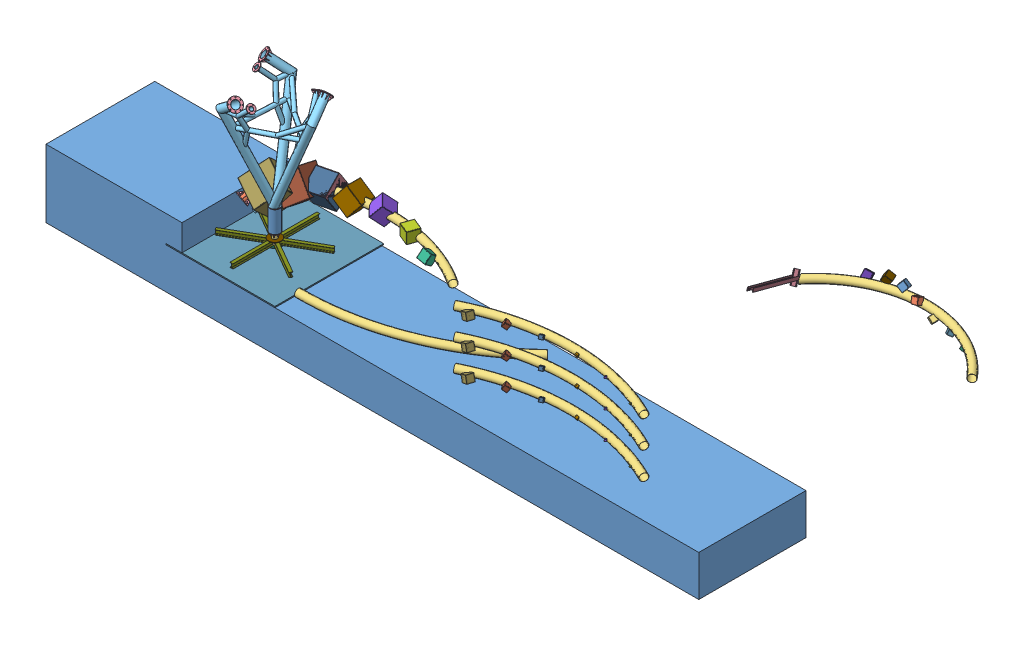
SolidWorks assembly loaded truck, configuration Default. Lengths in mm.
Overall size (16211.83 6656.86 12920.37).
99 component instances, 48 part files, 12 mates.
Components (placement in the parent):
- truck-1: truck [Default] at origin size (14630.4 1524 2438.4)
- tube1A-1: tube1A [Default] at (5444.0248 1828.8 -1151.975) size (10304.8 4797.57 11903.29)
  - tube1^tube1A-1: tube1^tube1A [A] at origin size (5509.57 567.54 3868.09) (virtual)
    - short-tube^tube1_tube1A-1: short-tube^tube1_tube1A [Default<As Machined>] at (-2066.9857 0 -335.3072) x (0.280011 0.524542 -0.804021) z (0.396988 0.699289 0.594471) size (592.32 168.28 168.28) (virtual)
    - tubes-1: tubes [tube1A] at origin size (5509.57 179.56 3868.09)
    - pipe_flange-1: pipe_flange [Default] at (-2222.5526 -291.4219 111.3861) x (0.228255 0.777129 0.58649) z (0.280011 0.524542 -0.804021) size (279.4 279.4 111.05)
  -  tube1-support-arm^tube1A-1:  tube1-support-arm^tube1A [Default] at (-1841.3383 3296.5765 733.9451) x (0.486192 -0.007064 0.873823) z (0.120148 -0.98993 -0.074853) size (412.01 1066.18 424.01) (virtual)
  - cube_positions-1: cube_positions [Default] at (-1823.1764 -3408.8204 760.8644) x (0.483946 0.016768 0.874937) z (-0.868168 0.134776 0.477619) size (10173.18 3894.08 5705.72) (hidden)
  - cube_21-2: cube_21 [Default] at (1288.2494 29.6746 -537.6975) x (0.984604 -0.16863 0.046022) z (-0.163622 -0.79651 0.582065) size (201.3 201.3 201.3)
  - cube_22-2: cube_22 [Default] at (645.1566 57.3606 -803.1505) x (0.933595 -0.053544 0.354308) z (-0.041789 -0.998295 -0.040754) size (257.18 257.18 257.18)
  - cube_23-2: cube_23 [Default] at (-109.9957 38.0914 -951.4494) x (0.687918 -0.154019 0.709258) z (-0.466636 0.654617 0.59475) size (324.08 323.21 324.08)
  - cube_24-2: cube_24 [Default] at (-714.1695 -0.9056 -890.2015) x (0.799244 -0.59975 -0.038856) z (0.182734 0.180907 0.966375) size (396.88 396.88 396.88)
  - cube_25-2: cube_25 [Default] at (-1245.7406 -40.6251 -805.9879) x (0.987297 0.085082 -0.134183) z (0.001435 0.839726 0.543009) size (473.08 473.08 473.08)
  - cube_26-2: cube_26 [Default] at (-1667.5795 -86.266 -627.0985) x (0.64678 -0.746775 0.15493) z (0.176738 0.344365 0.92205) size (549.27 549.27 549.27)
  - cube_27-2: cube_27 [Default] at (-1978.9147 -133.1093 -276.4109) x (0.852088 -0.443054 0.278657) z (0.115039 0.677912 0.726086) size (622.94 622.94 622.94)
  - boundry_cube-1: boundry_cube [cube25] at (-1244.4232 -38.3056 -806.6548) x (0.987297 0.085082 -0.134183) z (0.158877 -0.536304 0.828937) size (469.9 469.9 469.9)
  - boundry_cube-2: boundry_cube [cube26] at (-1667.1479 -83.6306 -626.4438) x (0.741916 0.568981 -0.354712) z (0.176738 0.344365 0.92205) size (546.1 546.1 546.1) (hidden)
  - boundry_cube-3: boundry_cube [cube27] at (-1979.2742 -130.3985 -276.6986) x (0.510601 0.586633 -0.628609) z (0.115039 0.677912 0.726086) size (619.76 619.76 619.76) (hidden)
- central_structure-1: central_structure [Default] at (3849.3756 1064.3199 -1156.3899) x (1 0 0) z (0 1 0) size (2438.4 2438.4 3268.86)
  - reference_cubes-1: reference_cubes [Default] at origin size (10937.47 5524.84 3894.08) (hidden)
  - scaffolding^central_structure-1: scaffolding^central_structure [Default] at (0 0 -124.5199) x (-1 0 0) z (0 1 0) size (2438.4 25.4 2438.4) (virtual)
    - reference_ground^scaffolding_central_structure-1: reference_ground^scaffolding_central_structure [Default] x (-1 0 0) z (0 1 0) size (2438.4 2438.4 25.4) (virtual)
  - ground_anchor-1: ground_anchor [Default] at (0 0 -124.5199) x (-1 0 0) z (0 1 0) size (1722.09 120.65 1949.45)
    - Copy of ground_anchor_ref^ground_anchor-1: Copy of ground_anchor_ref^ground_anchor [Default] at origin size (279.4 0 279.4) (virtual)
    - low_plate^ground_anchor-1: low_plate^ground_anchor [Default] at origin size (279.4 9.53 279.4) (virtual)
    - S Section_AI-1: S Section_AI [S4x7.7x36] at (-33.8201 9.525 -517.525) size (67.64 101.6 914.4)
    - S Section_AI-3: S Section_AI [S4x7.7x36] at (-465.0998 9.525 -229.4734) x (0.5 0 -0.866025) z (0.866025 0 0.5) size (67.64 101.6 914.4)
    - S Section_AI-4: S Section_AI [S4x7.7x36] at (-431.2797 9.525 288.0516) x (-0.5 0 -0.866025) z (0.866025 0 -0.5) size (67.64 101.6 914.4)
    - S Section_AI-5: S Section_AI [S4x7.7x36] at (33.8201 9.525 517.525) x (-1 0 0) z (0 0 -1) size (67.64 101.6 914.4)
    - S Section_AI-6: S Section_AI [S4x7.7x36] at (465.0998 9.525 229.4734) x (-0.5 0 0.866025) z (-0.866025 0 -0.5) size (67.64 101.6 914.4)
    - S Section_AI-7: S Section_AI [S4x7.7x36] at (431.2797 9.525 -288.0516) x (0.5 0 0.866025) z (-0.866025 0 0.5) size (67.64 101.6 914.4)
    - mid_plate^ground_anchor-2: mid_plate^ground_anchor [Default] at origin size (146.05 9.53 146.05) (virtual)
    - top_plate^ground_anchor-1: top_plate^ground_anchor [Default] at (0 111.125 0) x (-1 0 0) z (0 1 0) size (279.4 279.4 9.53) (virtual)
  - base_pin^central_structure-1: base_pin^central_structure [Default] at (0 0 367.6051) x (1 0 0) z (0 -1 0) size (219.07 736.6 219.07) (virtual)
    - tube^base_pin_central_structure-1: tube^base_pin_central_structure [Default] at origin size (219.07 482.6 219.07) (virtual)
    - plate^base_pin_central_structure-1: plate^base_pin_central_structure [Default] at (0 -254 0) size (219.07 12.7 219.07) (virtual)
    - plate^base_pin_central_structure-2: plate^base_pin_central_structure [Default] at (0 241.3 0) size (219.07 12.7 219.07) (virtual)
    - pin^base_pin_central_structure-1: pin^base_pin_central_structure [Default] at (0 -368.3 0) size (114.3 228.6 114.3) (virtual)
    - gusset^base_pin_central_structure-1: gusset^base_pin_central_structure [Default] at (0 -241.3 0) x (-1 0 0) z (0 0 -1) size (52.39 88.9 9.53) (virtual)
    - gusset^base_pin_central_structure-2: gusset^base_pin_central_structure [Default] at (0 -241.3 0) x (-0.5 0 -0.866025) z (0.866025 0 -0.5) size (52.39 88.9 9.53) (virtual)
    - gusset^base_pin_central_structure-3: gusset^base_pin_central_structure [Default] at (0 -241.3 0) x (0.5 0 -0.866025) z (0.866025 0 0.5) size (52.39 88.9 9.53) (virtual)
    - gusset^base_pin_central_structure-4: gusset^base_pin_central_structure [Default] at (0 -241.3 0) size (52.39 88.9 9.53) (virtual)
    - gusset^base_pin_central_structure-5: gusset^base_pin_central_structure [Default] at (0 -241.3 0) x (0.5 0 0.866025) z (-0.866025 0 0.5) size (52.39 88.9 9.53) (virtual)
    - gusset^base_pin_central_structure-6: gusset^base_pin_central_structure [Default] at (0 -241.3 0) x (-0.5 0 0.866025) z (-0.866025 0 -0.5) size (52.39 88.9 9.53) (virtual)
  - tubes^central_structure-1: tubes^central_structure [Default<As Machined>] at origin size (1730.45 1786.14 2430.89) (virtual)
  - pipe_flange-4: pipe_flange [Default] at (-40.8618 -842.5697 2971.914) x (-0.647876 -0.272848 0.711204) z (-0.761452 0.20604 -0.614604) size (279.4 279.4 111.05)
  - pipe_flange-5: pipe_flange [Default] at (-709.2559 456.6722 2971.914) x (0.087644 0.697501 0.711204) z (0.559162 0.556417 -0.614604) size (279.4 279.4 111.05)
  - pipe_flange-6: pipe_flange [Default] at (750.1177 385.8975 2971.914) x (0.560231 -0.424653 0.711204) z (0.20229 -0.762457 -0.614604) size (279.4 279.4 111.05)
  - pipe_flange-10: pipe_flange [Sch40_3_inch] at (125.9153 -655.6721 2881.7665) x (-0.595866 -0.523692 0.608844) z (-0.726669 0.028829 -0.686383) size (177.8 177.8 57.15)
  - pipe_flange-11: pipe_flange [Sch40_3_inch] at (-630.7864 218.7903 2881.7665) x (-0.155598 0.777881 0.608844) z (0.388301 0.614899 -0.686383) size (177.8 177.8 57.15)
  - pipe_flange-12: pipe_flange [Sch40_3_inch] at (504.8711 436.8819 2881.7665) x (0.751464 -0.254189 0.608844) z (0.338368 -0.643728 -0.686383) size (177.8 177.8 57.15)
  - positioning_ring^central_structure-1: positioning_ring^central_structure [Default] at (-467.1227 -648.6433 2658.0072) x (-0.32518 0.316298 -0.891186) z (0.945415 0.129823 -0.298891) size (41.91 20.96 5.08) (virtual)
  - positioning_ring^central_structure-2: positioning_ring^central_structure [Default] at (-328.1802 728.8618 2658.0072) x (0.436513 0.123465 -0.891186) z (-0.360278 -0.883665 -0.298891) size (41.91 20.96 5.08) (virtual)
  - positioning_ring^central_structure-3: positioning_ring^central_structure [Default] at (795.303 -80.2185 2658.0072) x (-0.111332 -0.439764 -0.891186) z (-0.585137 0.753842 -0.298891) size (41.91 20.96 5.08) (virtual)
- tube2A-1: tube2A [Default] at (10761.5629 1905 -128.1175) size (5548.73 212.13 5064.2)
  - tubes-1: tubes [tube2A] at origin size (5548.73 168.28 5064.2)
  - cube_15-2: cube_15 [Default] at (1757.1943 7.1888 -324.7748) x (0.466813 -0.378836 0.799105) z (-0.87943 -0.103618 0.464614) size (31.12 31.12 31.12)
  - cube_16-2: cube_16 [Default] at (968.8015 9.4519 -559.7177) x (0.806784 -0.069825 -0.586706) z (0.590423 0.132849 0.796085) size (41.27 41.27 42.23)
  - cube_17-2: cube_17 [Default] at (219.4124 11.792 -668.2944) x (0.954748 -0.289413 -0.068523) z (-0.098768 -0.525851 0.844823) size (59.24 59.06 59.06)
  - cube_18-2: cube_18 [Default] at (-522.2233 15.3473 -617.0525) x (0.916882 -0.004667 -0.399132) z (0.359767 0.442803 0.821276) size (81.92 81.92 84.87)
  - cube_19-2: cube_19 [Default] at (-1183.1884 -5.1426 -489.4193) x (0.660298 -0.557655 -0.503018) z (0.583277 -0.041114 0.811232) size (112.39 112.39 112.56)
  - cube_20-2: cube_20 [Default] at (-1812.0839 -23.6863 -257.1651) x (-0.350316 0.927365 -0.131426) z (-0.262185 0.037617 0.964284) size (157.73 157.73 159.27)
- tube2A-3: tube2A [Default] at (10761.5629 1295.4 -128.1175) size (5548.73 212.13 5064.2)
  - tubes-1: tubes [tube2A] at origin size (5548.73 168.28 5064.2)
  - cube_15-2: cube_15 [Default] at (1757.1943 7.1888 -324.7748) x (0.466813 -0.378836 0.799105) z (-0.87943 -0.103618 0.464614) size (31.12 31.12 31.12)
  - cube_16-2: cube_16 [Default] at (968.8015 9.4519 -559.7177) x (0.806784 -0.069825 -0.586706) z (0.590423 0.132849 0.796085) size (41.27 41.27 42.23)
  - cube_17-2: cube_17 [Default] at (219.4124 11.792 -668.2944) x (0.954748 -0.289413 -0.068523) z (-0.098768 -0.525851 0.844823) size (59.24 59.06 59.06)
  - cube_18-2: cube_18 [Default] at (-522.2233 15.3473 -617.0525) x (0.916882 -0.004667 -0.399132) z (0.359767 0.442803 0.821276) size (81.92 81.92 84.87)
  - cube_19-2: cube_19 [Default] at (-1183.1884 -5.1426 -489.4193) x (0.660298 -0.557655 -0.503018) z (0.583277 -0.041114 0.811232) size (112.39 112.39 112.56)
  - cube_20-2: cube_20 [Default] at (-1812.0839 -23.6863 -257.1651) x (-0.350316 0.927365 -0.131426) z (-0.262185 0.037617 0.964284) size (157.73 157.73 159.27)
- tube2A-4: tube2A [Default] at (10761.5629 2514.6 -128.1175) size (5548.73 212.13 5064.2)
  - tubes-1: tubes [tube2A] at origin size (5548.73 168.28 5064.2)
  - cube_15-2: cube_15 [Default] at (1757.1943 7.1888 -324.7748) x (0.466813 -0.378836 0.799105) z (-0.87943 -0.103618 0.464614) size (31.12 31.12 31.12)
  - cube_16-2: cube_16 [Default] at (968.8015 9.4519 -559.7177) x (0.806784 -0.069825 -0.586706) z (0.590423 0.132849 0.796085) size (41.27 41.27 42.23)
  - cube_17-2: cube_17 [Default] at (219.4124 11.792 -668.2944) x (0.954748 -0.289413 -0.068523) z (-0.098768 -0.525851 0.844823) size (59.24 59.06 59.06)
  - cube_18-2: cube_18 [Default] at (-522.2233 15.3473 -617.0525) x (0.916882 -0.004667 -0.399132) z (0.359767 0.442803 0.821276) size (81.92 81.92 84.87)
  - cube_19-2: cube_19 [Default] at (-1183.1884 -5.1426 -489.4193) x (0.660298 -0.557655 -0.503018) z (0.583277 -0.041114 0.811232) size (112.39 112.39 112.56)
  - cube_20-2: cube_20 [Default] at (-1812.0839 -23.6863 -257.1651) x (-0.350316 0.927365 -0.131426) z (-0.262185 0.037617 0.964284) size (157.73 157.73 159.27)
- tube4A-1: tube4A [Default] at (11562.999 2511.1486 -4732.0499) x (0.194163 -0.849473 0.490608) z (0.490608 0.517175 0.701309) size (11936.67 6342.03 7419.9)
  - cube_positions-1: cube_positions [Default] at (8904.7669 0 -1666.8962) x (-0.98414 0 0.177396) z (-0.177396 0 -0.98414) size (10173.18 3894.08 5705.72) (hidden)
  - ground_anchor^tube4A-1: ground_anchor^tube4A [Default] at (9566.8333 -60.325 -1104.0246) x (-0.999452 0 0.033088) z (0 -1 0) size (470.34 5095.97 101.6) (virtual)
  - tubes-1: tubes [tube4A] at (840.8937 1535.1212 -511.9514) x (0.194163 0.849473 0.490608) z (0.490608 -0.517175 0.701309) size (5156.33 178.46 3757.36)
  - cube_06-2: cube_06 [Default] at (471.5315 2748.7735 -1138.0748) x (0.201369 0.905147 -0.374379) z (0.964745 -0.249399 -0.084066) size (112.39 112.39 116.4)
  - cube_07-2: cube_07 [Default] at (645.566 3070.0096 -753.4371) x (0.234737 0.447214 -0.863075) z (0.927023 -0.370117 0.060349) size (97.16 97.16 101.09)
  - cube_08-2: cube_08 [Default] at (942.6163 3319.9065 -214.0269) x (-0.520827 0.525094 -0.673064) z (0.853659 0.322603 -0.408894) size (81.92 81.92 85.85)
  - cube_01-2: cube_01 [Default] at (-37.904 1151.3192 -1919.5434) x (-0.033713 0.00175 0.99943) z (-0.959686 0.279148 -0.032861) size (163.19 163.19 163.19)
  - cube_02-2: cube_02 [Default] at (-88.0911 1506.3364 -1758.7081) x (0.627621 -0.148413 0.764242) z (-0.63488 0.470576 0.612769) size (158.12 158.12 158.12)
  - cube_03-2: cube_03 [Default] at (-39.521 1804.2306 -1588.2847) x (0.643801 0.761931 -0.070581) z (-0.729232 0.638874 0.245073) size (150.61 150.49 150.49)
  - cube_04-2: cube_04 [Default] at (125.08 2085.0042 -1403.7965) x (0.992472 0.073499 -0.097969) z (-0.011929 0.85412 0.519939) size (140.33 142.17 140.33)
  - cube_05-2: cube_05 [Default] at (346.6784 2408.9309 -1315.8693) x (0.718959 0.693701 0.043313) z (-0.249968 0.199916 0.947391) size (127.64 128.2 127.64)
- tube3A-1: tube3A [Default] at (7335.3837 1295.4 -1113.8417) x (-0.929213 0 0.369544) z (-0.369544 0 -0.929213) size (5554.54 175.44 6144.47)
  - cube_positions-1: cube_positions [Default] at (-2670.6643 -3280.6684 6355.7547) x (0.67216 -0.00431 -0.740393) z (0.73275 0.147305 0.664364) size (10173.18 3894.08 5705.72) (suppressed, hidden)
  - tubes-1: tubes [tube3A] at origin size (5554.54 168.28 6144.47)
  - cube_09-2: cube_09 [Default] at (1891.328 -39.9576 -219.9855) x (0.558213 -0.291956 0.776634) z (-0.686222 0.363684 0.629947) size (66.67 66.67 66.67)
  - cube_10-2: cube_10 [Default] at (1228.5614 -17.4711 -418.2438) x (-0.71669 -0.609869 -0.338254) z (-0.59783 0.78702 -0.152311) size (53.98 55.56 54.09)
  - cube_11-2: cube_11 [Default] at (417.5304 -1.7159 -528.0192) x (0.316006 -0.604945 0.730877) z (0.798081 0.586057 0.140015) size (46.52 46.39 46.35)
  - cube_12-2: cube_12 [Default] at (-358.2393 3.7306 -535.1453) x (0.586492 0.345764 0.732445) z (-0.809811 0.233265 0.538324) size (33.65 33.65 33.65)
  - cube_13-2: cube_13 [Default] at (-1020.6914 4.0423 -454.5155) x (0.910611 -0.27141 0.311647) z (0.00891 0.76683 0.641789) size (28.57 28.57 28.57)
  - cube_14-2: cube_14 [Default] at (-1799.1926 16.7711 -254.42) x (0.802946 -0.45597 -0.383887) z (0.528044 0.2454 0.812987) size (20.96 20.96 20.96)
Mates (geometry in assembly coordinates):
- Coincident2: coincident anti-aligned: plane of truck-1 through (2985.7756 914.4 -2340.2818) normal (0 1 0); plane of central_structure-1/scaffolding^central_structure-1/reference_ground^scaffolding_central_structure-1 through (2630.1756 914.4 62.8101) normal (0 -1 0)
- Coincident3: coincident aligned: plane of truck-1 through (-62.2244 1524 62.8101) normal (0 0 1); plane of central_structure-1/scaffolding^central_structure-1/reference_ground^scaffolding_central_structure-1 through (5068.5756 914.4 62.8101) normal (0 0 1)
- Distance2: distance = 355.6 mm anti-aligned: plane of truck-1 through (2985.7756 1524 -2375.5899) normal (1 0 0); plane of central_structure-1/scaffolding^central_structure-1/reference_ground^scaffolding_central_structure-1 through (2630.1756 914.4 -2375.5899) normal (-1 0 0)
- Distance4: distance = 914.4 mm: point of tube1A-1/tube1^tube1A-1/tubes-1; plane of truck-1 through (2985.7756 914.4 -2340.2818) normal (0 1 0)
- Concentric2: concentric aligned: circle of tube2A-1/tubes-1; circle of tube2A-4/tubes-1
- Distance6: distance = 609.6 mm: point of tube2A-4/tubes-1; point of tube2A-1/tubes-1
- Concentric3: concentric aligned: circle of tube2A-3/tubes-1; circle of tube2A-4/tubes-1
- Distance8: distance = 1219.2 mm: point of tube2A-3/tubes-1; point of tube2A-4/tubes-1
- Distance9: distance = 381 mm: point of tube2A-3/tubes-1; plane of truck-1 through (2985.7756 914.4 -2340.2818) normal (0 1 0)
- Parallel5: parallel aligned: plane of truck-1 through (2985.7756 914.4 -2340.2818) normal (0 1 0); plane of tube4A-1
- Distance12: distance = 457.2 mm aligned: plane of tube4A-1; plane of truck-1 through (2985.7756 914.4 -2340.2818) normal (0 1 0)
- Distance13: distance = 381 mm: point of tube3A-1/tubes-1; plane of truck-1 through (2985.7756 914.4 -2340.2818) normal (0 1 0)
